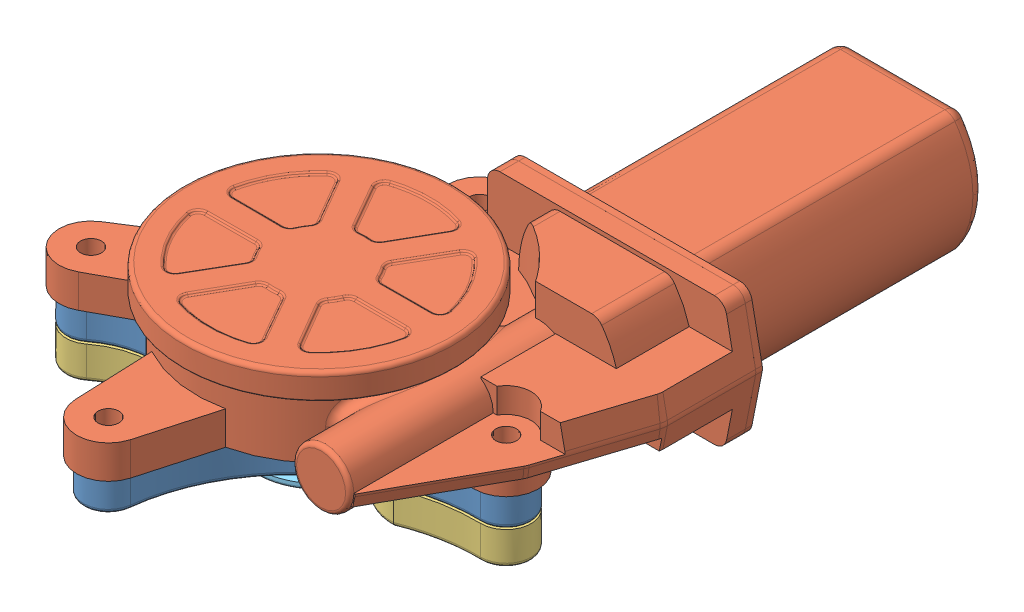
SolidWorks assembly Montagem1, configuration Valor predeterminado. Lengths in mm.
Overall size (113.16 39.06 167.15).
5 component instances, 5 part files, 7 mates.
Components (placement in the parent):
- base-1: base [Valor predeterminado] at (-73.3678 23.5001 125.5688) x (1 0 0) z (0 -1 0) size (100.5 101.2 8)
- Motor Vidro Elétrico Mabuchi Direito 02-1: Motor Vidro Elétrico Mabuchi Direito 02 [Valor predeterminado] at (-41.3678 31.0001 16.6688) size (113.16 31.51 167.15)
- suporte_adaptador-2: suporte_adaptador [Valor predeterminado] at (-73.3687 15.5001 125.5917) x (1 0 0) z (0 -1 0) size (100.5 39.8 8.06)
- Bolinha-2: Bolinha [Valor predeterminado] at (-72.4584 11.9148 113.6598) x (0.230061 0.763416 -0.603546) z (-0.527257 0.61905 0.582046) size (4.5 4.5 4.5)
- adaptador_motor-3: adaptador_motor [Valor predeterminado] at (-73.3678 11.5001 125.5688) x (0.997497 0 -0.070708) z (0 1 0) size (30 30 16.5)
Mates (geometry in assembly coordinates):
- Concêntrico1: concentric aligned: cylinder of base-1 through (-28.3678 15.5001 125.5688) axis (0 1 0) radius 2.5; cylinder of Motor Vidro Elétrico Mabuchi Direito 02-1 through (-28.3678 227.7961 125.5688) axis (0 1 0) radius 2.5
- Concêntrico3: concentric aligned: cylinder of base-1 through (-116.8678 15.5001 136.8688) axis (0 1 0) radius 2.5; cylinder of Motor Vidro Elétrico Mabuchi Direito 02-1 through (-116.8678 227.7961 136.8688) axis (0 1 0) radius 2.5
- Coincidente1: coincident anti-aligned: plane of base-1 through (-90.2946 23.5001 163.5914) normal (0 1 0); plane of Motor Vidro Elétrico Mabuchi Direito 02-1 through (-67.1334 23.5001 84.6497) normal (0 -1 0)
- Coincidente10: coincident anti-aligned: plane of base-1 through (-90.2946 15.5001 163.5914) normal (0 -1 0); plane of suporte_adaptador-2 through (-101.2225 15.5001 157.0369) normal (0 1 0)
- Coincidente11: coincident anti-aligned: plane of Motor Vidro Elétrico Mabuchi Direito 02-1 through (-73.3678 15.0001 133.3968) normal (0 -1 0); plane of adaptador_motor-3 through (-78.848 15.0001 118.2897) normal (0 1 0)
- Concêntrico4: concentric anti-aligned: cylinder of base-1 through (-73.3678 15.5001 125.5688) axis (0 1 0) radius 15; cylinder of adaptador_motor-3 through (-73.3678 15.5001 125.5688) axis (0 -1 0) radius 15
- Concêntrico6: concentric: sphere of Bolinha-2; sphere of adaptador_motor-3
